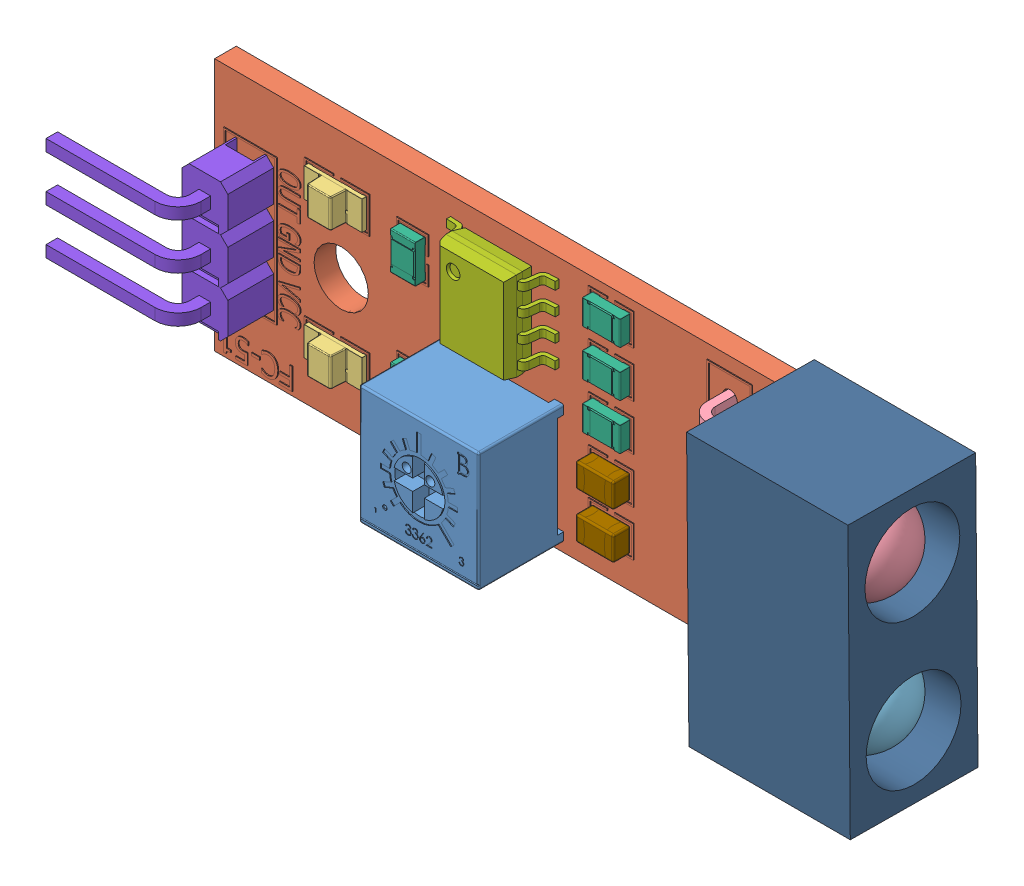
SolidWorks assembly ensamble_IR_Case, configuration Predeterminado. Lengths in mm.
Overall size (48.9 15.11 8.19).
19 component instances, 10 part files, 0 mates.
Components (placement in the parent):
- Sensor_IR.stp-1: Sensor_IR.stp [Predeterminado] at (21.1783 -3.492 43.0431) size (45.22 14 7.87)
  - 3362P-1-102LF.stp-1: 3362P-1-102LF.stp [Predeterminado] at (0.5 -3.2 1.53) x (1 0 0) z (0 -1 0) size (6.6 7.58 6.6)
  - IR_Sensor_FC-51_1.stp-1: IR_Sensor_FC-51_1.stp [Predeterminado] at origin size (31 14 1.25)
  - KPTR-3216CGCK.stp-1: KPTR-3216CGCK.stp [Predeterminado] at (-8.7 3.8 1.45) x (1 0 0) z (0 0 -1) size (3.2 1.6 1.05)
  - KPTR-3216CGCK.stp-2: KPTR-3216CGCK.stp [Predeterminado] at (-8.7 -3.8 1.45) x (1 0 0) z (0 0 -1) size (3.2 1.6 1.05)
  - LED 5mm.stp-1: LED 5mm.stp [Predeterminado] at (15.74 3.64 3) x (0 1 0) z (1 0 0) size (5.5 6.7 11.78)
  - LED 5mm_foto.stp-1: LED 5mm_foto.stp [Predeterminado] at (15.74 -3.64 3) x (0 1 0) z (1 0 0) size (5.5 6.7 11.78)
  - RESC-0805.stp-1: RESC-0805.stp [Predeterminado] at (-4.525 -3.15 1.2) x (0 -1 0) z (0 0 1) size (2.1 1.35 0.6)
  - RESC-0805.stp-2: RESC-0805.stp [Predeterminado] at (-4.525 3.25 1.2) x (0 1 0) z (0 0 1) size (2.1 1.35 0.6)
  - SOIC8-150-50.stp-1: SOIC8-150-50.stp [Predeterminado] at (0.55 3.85 1.2) x (1 0 0) z (0 -1 0) size (6 1.91 4.9)
  - 1 Pin 2.54 mm Right Angle Single Row Pin Header Male 90 degrees Needle Connector.stp-1: 1 Pin 2.54 mm Right Angle Single Row Pin Header Male 90 degrees Needle Connector.stp [Predeterminado] at (-13.5 2.54 -1.76) x (-1 0 0) z (0 0 1) size (8.45 2.54 7.3)
  - 1 Pin 2.54 mm Right Angle Single Row Pin Header Male 90 degrees Needle Connector.stp-2: 1 Pin 2.54 mm Right Angle Single Row Pin Header Male 90 degrees Needle Connector.stp [Predeterminado] at (-13.5 0 -1.76) x (-1 0 0) z (0 0 1) size (8.45 2.54 7.3)
  - 1 Pin 2.54 mm Right Angle Single Row Pin Header Male 90 degrees Needle Connector.stp-3: 1 Pin 2.54 mm Right Angle Single Row Pin Header Male 90 degrees Needle Connector.stp [Predeterminado] at (-13.5 -2.54 -1.76) x (-1 0 0) z (0 0 1) size (8.45 2.54 7.3)
  - RESC-0805.stp-3: RESC-0805.stp [Predeterminado] at (6.45 5.625 1.2) size (2.1 1.35 0.6)
  - RESC-0805.stp-4: RESC-0805.stp [Predeterminado] at (6.45 3.085 1.2) size (2.1 1.35 0.6)
  - RESC-0805.stp-5: RESC-0805.stp [Predeterminado] at (6.45 0.545 1.2) size (2.1 1.35 0.6)
  - CAPC-0805-T0.95-BN.stp-1: CAPC-0805-T0.95-BN.stp [Predeterminado] at (6.45 -1.995 1.2) size (2.1 1.35 0.95)
  - CAPC-0805-T0.95-BN.stp-2: CAPC-0805-T0.95-BN.stp [Predeterminado] at (6.45 -4.535 1.2) size (2.1 1.35 0.95)
- limiteIR-1: limiteIR [Predeterminado] at (36.9552 0.3002 45.8639) x (-0.008726 0.999962 -0.000076) z (0.008727 0 -0.999962) size (15 12.31 7)
